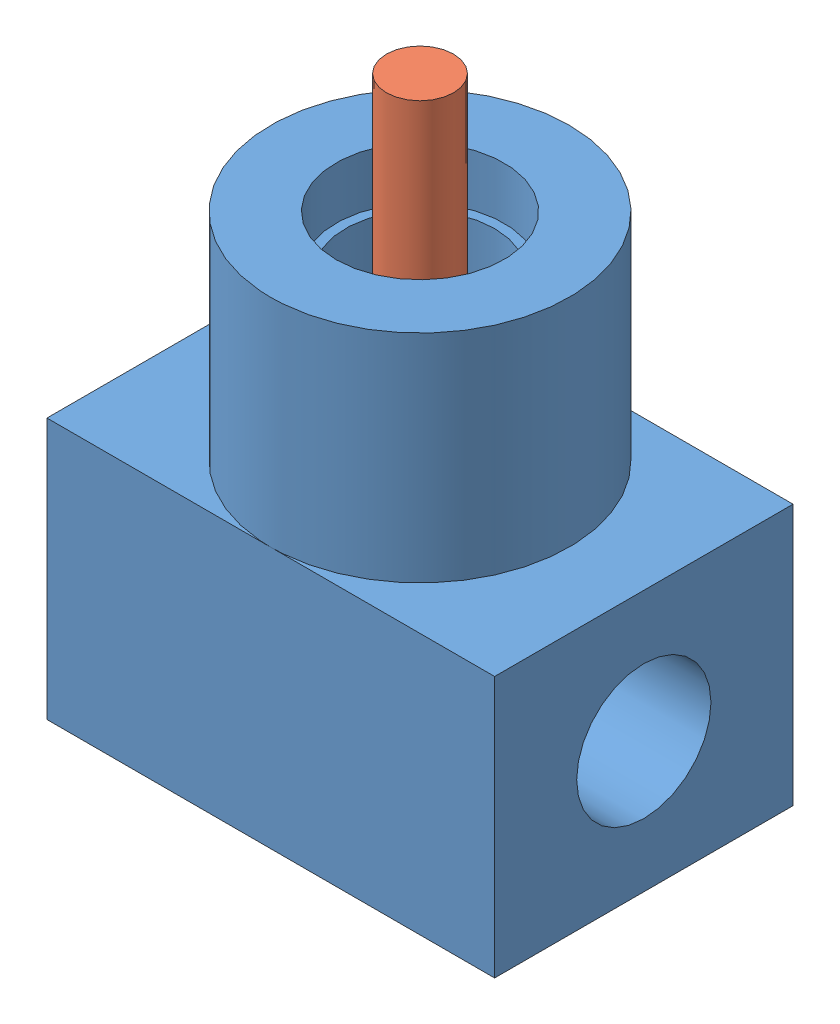
SolidWorks assembly Assemblage1, configuration Défaut. Lengths in mm.
Overall size (120 160 80).
2 component instances, 2 part files, 2 mates.
Components (placement in the parent):
- Assemblage1-2: Assemblage1 [Défaut] at (-29.557 -5.7951 128) size (120 128 80)
- Assemblage2-5: Assemblage2 [Défaut] at (-29.557 119.2049 168) x (1 0 0) z (0 -1 0) size (45 45 124)
Mates (geometry in assembly coordinates):
- Coïncidente3: coincident anti-aligned: axis of Assemblage1-2 through (-29.557 87.2049 168) axis (0 -1 0); axis of Assemblage2-5 through (-29.557 49.5043 168) axis (0 1 0)
- Coïncidente4: coincident anti-aligned: plane of Assemblage1-2 through (-89.557 29.2049 208) normal (0 1 0); plane of Assemblage2-5 through (-29.557 29.2049 168.7945) normal (0 -1 0)
